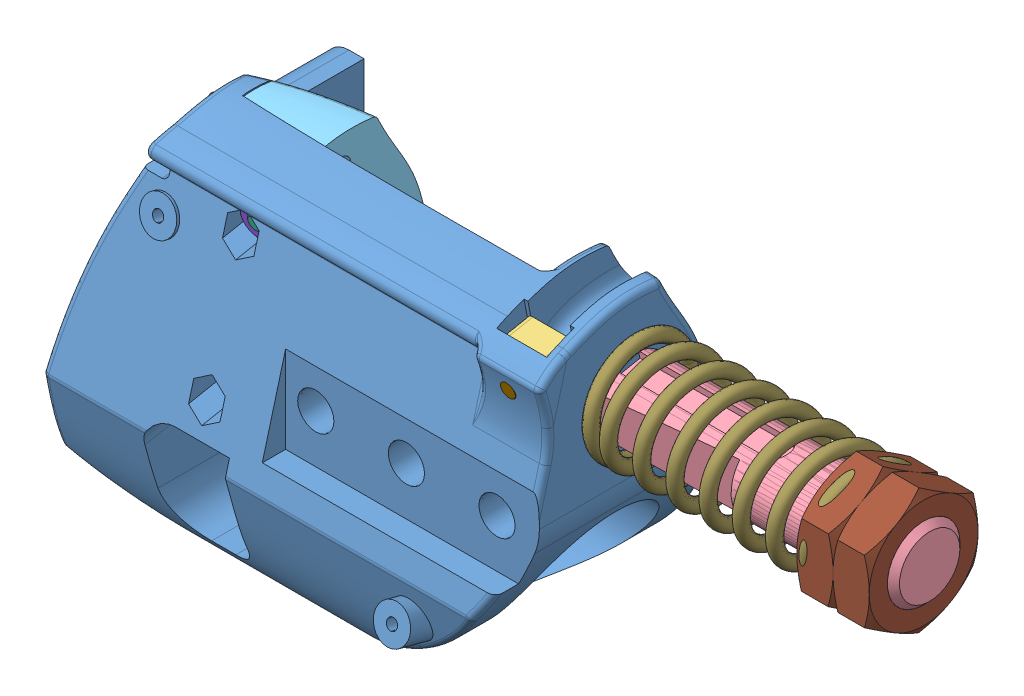
SolidWorks assembly a-motorträger-beine-rechts-v01, configuration 01. Lengths in mm.
Overall size (130.38 65.2 41.28).
22 component instances, 15 part files, 85 mates.
Components (placement in the parent):
- p-halterreferenz-rechts-v04-1: p-halterreferenz-rechts-v04 [01] at (-8 0 0) x (0 0 -1) z (1 0 0) size (41.28 65.2 84.36)
- z-jfm-0608-06-v01-1: z-jfm-0608-06-v01 [01] at (-23.3 0 0) x (-1 0 0) z (0 0 -1) size (6 12 12)
- z-induktiv-sensor-v01-1: z-induktiv-sensor-v01 [01] at (29 21.9082 7.6275) x (1 0 0) z (0 0.190809 -0.981627) size (8 16 4.7)
- z-induktiv-sensor-v01-2: z-induktiv-sensor-v01 [01] at (-25.5 8.63 4) x (0 0 -1) z (-1 0 0) size (8 16 4.7)
- p-federstössel-v01-1: p-federstössel-v01 [01] at (77.9 27.8 -1.72) x (-1 0 0) z (0 -0.190809 0.981627) size (77 12 12)
- p-halterdeckel-rechts-v02-1: p-halterdeckel-rechts-v02 [01] at (-8 0 0) x (0 0 -1) z (1 0 0) size (28.27 33.45 14.71)
- z-passschraube-misumi-4-v01-1: z-passschraube-misumi-4-v01 [01] at (-13.1 35.2829 -8.5672) x (0 -0.190809 0.981627) z (-0.839411 -0.533511 -0.103704) size (18 6.5 6.5)
- z-passschraube-misumi-4-v01-2: z-passschraube-misumi-4-v01 [01] at (-13.1 16.1412 -12.288) x (0 -0.190809 0.981627) z (-0.58333 0.797312 0.154982) size (18 6.5 6.5)
- Lock washer DIN 6799 - 7-11: Lock washer DIN 6799 - 7 [Lock washer DIN 6799 - 7] at (24 27.8 -1.72) x (0 0 1) z (-1 0 0) size (14.3 11.94 0.9)
- Hexagon Nut ISO 4032 - M2.5 - W - N-19: Hexagon Nut ISO 4032 - M2.5 - W - N [Hexagon Nut ISO 4032 - M2.5 - W - N] at (-13.1 31.8991 8.8409) x (1 0 0) z (0 -0.190809 0.981627) size (5 5.77 2)
- Hexagon Nut ISO 4032 - M2.5 - W - N-20: Hexagon Nut ISO 4032 - M2.5 - W - N [Hexagon Nut ISO 4032 - M2.5 - W - N] at (-13.1 12.7574 5.1202) x (1 0 0) z (0 -0.190809 0.981627) size (5 5.77 2)
- DIN 7991 - M3 x 8 --- 4.8C-19: DIN 7991 - M3 x 8 --- 4.8C [DIN 7991 - M3 x 8 --- 4.8C] at (-30.15 20.63 0) size (8 5.7 5.7)
- DIN 7991 - M3 x 8 --- 4.8C-20: DIN 7991 - M3 x 8 --- 4.8C [DIN 7991 - M3 x 8 --- 4.8C] at (33 34.5749 5.3527) x (0 -0.190809 0.981627) z (-0.981627 0.187303 0.036408) size (8 5.7 5.7)
- p-oese-v01-1: p-oese-v01 [01] at (-25.5 37.4 0) size (3.5 4 4)
- Hexagon Thin Nut ISO 4035 - M12 - N-19: Hexagon Thin Nut ISO 4035 - M12 - N [Hexagon Thin Nut ISO 4035 - M12 - N] at (74.9 27.8 -1.72) x (0 -0.006521 -0.999979) z (-1 0 0) size (18 20.78 6)
- Hexagon Thin Nut ISO 4035 - M12 - N-20: Hexagon Thin Nut ISO 4035 - M12 - N [Hexagon Thin Nut ISO 4035 - M12 - N] at (80.9 27.8 -1.72) x (0 0 1) z (-1 0 0) size (18 20.78 6)
- z-feder-febrotec-v01-1: z-feder-febrotec-v01 [01] at (40 28.171 -1.6479) x (1 0 0) z (0 -0.190809 0.981627) size (40.25 20.98 20.5)
- p-seil-v02-1: p-seil-v02 [01] at (-16.85 -0.1381 -7.1506) x (-1 0 0) z (0 0.190809 -0.981627) size (48.5 39 1.5)
- p-umlenkpulley-v06-1: p-umlenkpulley-v06 [01] at (-13.1 33.728 -0.5677) x (0 -0.190809 0.981627) z (-0.981627 0.187303 0.036408) size (3.6 7.15 7.15)
- p-umlenkpulley-v06-4: p-umlenkpulley-v06 [01] at (-13.1 14.5863 -4.2885) x (0 -0.190809 0.981627) z (-0.997632 0.067518 0.013124) size (3.6 7.15 7.15)
- p-umlenkpulley-v06-3: p-umlenkpulley-v06 [01] at (14.9 27.8 -1.72) x (0 -0.190809 0.981627) z (-0.981627 0.187303 0.036408) size (3.6 7.15 7.15)
- Parallel Pin ISO 2338 - 4 h6 x 10 - St-11: Parallel Pin ISO 2338 - 4 h6 x 10 - St [Parallel Pin ISO 2338 - 4 h6 x 10 - St] at (14.9 28.754 -6.6281) x (0 -0.190809 0.981627) z (-0.981627 0.187303 0.036408) size (10 4 4)
Mates (geometry in assembly coordinates):
- Deckungsgleich4: coincident anti-aligned: plane of z-jfm-0608-06-v01-1 through (-23.3 0 0) normal (0 0 -1); plane of assembly through (0 0 0) normal (0 0 1)
- Deckungsgleich22: coincident aligned: plane of p-halterreferenz-rechts-v04-1; plane of assembly through (0 0 0) normal (0 1 0)
- Deckungsgleich23: coincident anti-aligned: plane of p-halterreferenz-rechts-v04-1 through (-8 0 0) normal (0 0 -1); plane of assembly through (0 0 0) normal (0 0 1)
- Konzentrisch3: concentric aligned: cylinder of z-induktiv-sensor-v01-2 through (-30.2 20.63 0) axis (-1 0 0) radius 1.55; cylinder of p-halterreferenz-rechts-v04-1 through (38.3169 20.63 0) axis (-1 0 0) radius 1.23
- Deckungsgleich25: coincident aligned: plane of z-induktiv-sensor-v01-2; plane of p-halterreferenz-rechts-v04-1 through (-8 0 0) normal (0 0 -1)
- Deckungsgleich26: coincident anti-aligned: plane of z-induktiv-sensor-v01-2 through (-25.5 8.63 4) normal (1 0 0); plane of p-halterreferenz-rechts-v04-1 through (-25.5 0 0) normal (-1 0 0)
- Konzentrisch4: concentric aligned: cylinder of p-halterreferenz-rechts-v04-1 through (-39.3597 27.8 -1.72) axis (1 0 0) radius 6.125; cylinder of p-federstössel-v01-1 through (77.9 27.8 -1.72) axis (1 0 0) radius 6
- Parallel3: parallel anti-aligned: plane of p-halterreferenz-rechts-v04-1 through (-39.3597 22.4213 -4.6501) normal (0 0.190809 -0.981627); plane of p-federstössel-v01-1 through (65.9 20.8194 -5.1143) normal (0 -0.190809 0.981627)
- Deckungsgleich32: coincident aligned: plane of p-halterreferenz-rechts-v04-1; plane of p-halterdeckel-rechts-v02-1
- Deckungsgleich33: coincident anti-aligned: plane of p-halterdeckel-rechts-v02-1 through (-8 0 0) normal (0 0 -1); plane of assembly through (0 0 0) normal (0 0 1)
- Deckungsgleich34: coincident aligned: plane of p-halterdeckel-rechts-v02-1 through (-8 0 0) normal (1 0 0); plane of p-halterreferenz-rechts-v04-1 through (-8 0 0) normal (1 0 0)
- Konzentrisch5: concentric aligned: cylinder of p-halterdeckel-rechts-v02-1 through (-13.1 36.3949 -14.2879) axis (0 0.190809 -0.981627) radius 2.075; cylinder of z-passschraube-misumi-4-v01-1 through (-13.1 35.2829 -8.5672) axis (0 0.190809 -0.981627) radius 2
- Deckungsgleich35: coincident anti-aligned: plane of p-halterdeckel-rechts-v02-1 through (-13.1 2.3168 -11.919) normal (0 0.190809 -0.981627); plane of z-passschraube-misumi-4-v01-1 through (-14.8664 37.3885 -5.1018) normal (0 -0.190809 0.981627)
- Konzentrisch7: concentric aligned: cylinder of p-halterdeckel-rechts-v02-1 through (-13.1 17.4154 -18.843) axis (0 0.190809 -0.981627) radius 2.075; cylinder of z-passschraube-misumi-4-v01-2 through (-13.1 16.1412 -12.288) axis (0 0.190809 -0.981627) radius 2
- Deckungsgleich36: coincident anti-aligned: plane of p-halterdeckel-rechts-v02-1 through (-13.1 2.3168 -11.919) normal (0 0.190809 -0.981627); plane of z-passschraube-misumi-4-v01-2 through (-10.4602 17.4298 -8.9813) normal (0 -0.190809 0.981627)
- Konzentrisch9: concentric anti-aligned: cylinder of p-federstössel-v01-1 through (77.9 27.8 -1.72) axis (1 0 0) radius 3.5; cylinder of Lock washer DIN 6799 - 7-11 through (24.9 27.8 -1.72) axis (-1 0 0) radius 3.5
- Deckungsgleich40: coincident anti-aligned: plane of p-federstössel-v01-1 through (24.9 21.9102 -2.8649) normal (-1 0 0); plane of Lock washer DIN 6799 - 7-11 through (24.9 27.8 -1.72) normal (1 0 0)
- Konzentrisch10: concentric anti-aligned: cylinder of p-halterreferenz-rechts-v04-1 through (-13.1 27.2158 32.9346) axis (0 0.190809 -0.981627) radius 1.5; cylinder of Hexagon Nut ISO 4032 - M2.5 - W - N-19 through (-13.1 32.2808 6.8777) axis (0 -0.190809 0.981627) radius 1.025
- Parallel4: parallel anti-aligned: plane of p-halterreferenz-rechts-v04-1 through (-15.7 28.6893 33.221) normal (0.5 -0.850114 -0.165245); plane of Hexagon Nut ISO 4032 - M2.5 - W - N-19 through (-13.1 35.1145 7.4285) normal (-0.5 0.850114 0.165245)
- Deckungsgleich42: coincident anti-aligned: plane of p-halterreferenz-rechts-v04-1 through (-8 -0.1129 0.581) normal (0 -0.190809 0.981627); plane of Hexagon Nut ISO 4032 - M2.5 - W - N-19 through (-13.1 35.1145 7.4285) normal (0 0.190809 -0.981627)
- Konzentrisch11: concentric anti-aligned: cylinder of p-halterreferenz-rechts-v04-1 through (-13.1 8.0741 29.2138) axis (0 0.190809 -0.981627) radius 1.5; cylinder of Hexagon Nut ISO 4032 - M2.5 - W - N-20 through (-13.1 13.139 3.1569) axis (0 -0.190809 0.981627) radius 1.025
- Parallel5: parallel anti-aligned: plane of p-halterreferenz-rechts-v04-1 through (-15.7 9.5476 29.5002) normal (0.5 -0.850114 -0.165245); plane of Hexagon Nut ISO 4032 - M2.5 - W - N-20 through (-13.1 15.9727 3.7077) normal (-0.5 0.850114 0.165245)
- Deckungsgleich44: coincident anti-aligned: plane of p-halterreferenz-rechts-v04-1 through (-8 -0.1129 0.581) normal (0 -0.190809 0.981627); plane of Hexagon Nut ISO 4032 - M2.5 - W - N-20 through (-13.1 15.9727 3.7077) normal (0 0.190809 -0.981627)
- Konzentrisch12: concentric aligned: cylinder of z-induktiv-sensor-v01-2 through (-30.2 20.63 0) axis (-1 0 0) radius 1.55; cylinder of DIN 7991 - M3 x 8 --- 4.8C-19 through (-30.15 20.63 0) axis (-1 0 0) radius 1.5
- Deckungsgleich45: coincident aligned: cone of z-induktiv-sensor-v01-2 through (-28.5 20.63 0) axis (1 0 0); cone of DIN 7991 - M3 x 8 --- 4.8C-19 through (-29.8 20.63 0) axis (1 0 0)
- Konzentrisch14: concentric aligned: cylinder of z-induktiv-sensor-v01-1 through (33 34.5845 5.3036) axis (0 0.190809 -0.981627) radius 1.55; cylinder of DIN 7991 - M3 x 8 --- 4.8C-20 through (33 34.5749 5.3527) axis (0 0.190809 -0.981627) radius 1.5
- Deckungsgleich46: coincident aligned: cone of z-induktiv-sensor-v01-1 through (33 34.2601 6.9724) axis (0 -0.190809 0.981627); cone of DIN 7991 - M3 x 8 --- 4.8C-20 through (33 34.5082 5.6962) axis (0 -0.190809 0.981627)
- Konzentrisch16: concentric anti-aligned: cylinder of p-halterreferenz-rechts-v04-1 through (-21.3635 37.4 0) axis (1 0 0) radius 2.15; cylinder of p-oese-v01-1 through (-25.5 37.4 0) axis (-1 0 0) radius 2
- Deckungsgleich47: coincident anti-aligned: plane of p-halterreferenz-rechts-v04-1 through (-25.5 39.55 0) normal (1 0 0); plane of p-oese-v01-1 through (-25.5 39.4 0) normal (-1 0 0)
- Konzentrisch17: concentric anti-aligned: cylinder of p-federstössel-v01-1 through (77.9 27.8 -1.72) axis (1 0 0) radius 6; cylinder of Hexagon Thin Nut ISO 4035 - M12 - N-19 through (80.9 27.8 -1.72) axis (-1 0 0) radius 5.1
- Abstand16: distance = 7 mm aligned: plane of Hexagon Thin Nut ISO 4035 - M12 - N-19 through (80.9 17.4079 -1.6522) normal (1 0 0); plane of p-federstössel-v01-1 through (87.9 21.9102 -2.8649) normal (1 0 0)
- Konzentrisch19: concentric anti-aligned: cylinder of p-federstössel-v01-1 through (77.9 27.8 -1.72) axis (1 0 0) radius 6; cylinder of Hexagon Thin Nut ISO 4035 - M12 - N-20 through (86.9 27.8 -1.72) axis (-1 0 0) radius 5.1
- Deckungsgleich49: coincident anti-aligned: plane of Hexagon Thin Nut ISO 4035 - M12 - N-19 through (80.9 17.4079 -1.6522) normal (1 0 0); plane of Hexagon Thin Nut ISO 4035 - M12 - N-20 through (80.9 38.1923 -1.72) normal (-1 0 0)
- Deckungsgleich50: coincident aligned: plane of p-federstössel-v01-1 through (77.9 27.8 -1.72) normal (0 -0.190809 0.981627); plane of z-feder-febrotec-v01-1 through (40 28.171 -1.6479) normal (0 -0.190809 0.981627)
- Abstand17: distance = 3 mm aligned: plane of z-feder-febrotec-v01-1; plane of p-halterreferenz-rechts-v04-1 through (37 0 0) normal (1 0 0)
- Konzentrisch20: concentric anti-aligned: cylinder of z-passschraube-misumi-4-v01-1 through (-13.1 35.2829 -8.5672) axis (0 0.190809 -0.981627) radius 2; cylinder of p-umlenkpulley-v06-1 through (-13.1 31.4085 11.3649) axis (0 -0.190809 0.981627) radius 2.075
- Deckungsgleich52: coincident aligned: plane of p-federstössel-v01-1 through (77.9 27.8 -1.72) normal (0 -0.190809 0.981627); plane of p-umlenkpulley-v06-1
- Konzentrisch21: concentric anti-aligned: cylinder of z-passschraube-misumi-4-v01-2 through (-13.1 16.1412 -12.288) axis (0 0.190809 -0.981627) radius 2; cylinder of p-umlenkpulley-v06-4 through (-13.1 12.2668 7.6441) axis (0 -0.190809 0.981627) radius 2.075
- Deckungsgleich53: coincident aligned: plane of p-umlenkpulley-v06-1 through (-12.4179 37.5163 -1.665) normal (0 0.190809 -0.981627); plane of p-umlenkpulley-v06-4 through (-12.8541 18.4307 -5.3749) normal (0 0.190809 -0.981627)
- Konzentrisch22: concentric: cylinder of z-passschraube-misumi-4-v01-1 through (-13.1 35.2829 -8.5672) axis (0 0.190809 -0.981627) radius 2; point of p-seil-v02-1
- Konzentrisch23: concentric: cylinder of z-passschraube-misumi-4-v01-2 through (-13.1 16.1412 -12.288) axis (0 0.190809 -0.981627) radius 2; point of p-seil-v02-1
- Deckungsgleich57: coincident anti-aligned: plane of p-seil-v02-1 through (-16.85 -0.1381 -7.1506) normal (0 0.190809 -0.981627); plane of p-umlenkpulley-v06-1
- Deckungsgleich59: coincident anti-aligned: plane of p-halterreferenz-rechts-v04-1 through (-8 0 0) normal (0 0 -1); plane of assembly through (0 0 0) normal (0 0 1)
- Abstand18: distance = 8 mm aligned: plane of assembly through (0 0 0) normal (1 0 0); plane of p-halterreferenz-rechts-v04-1 through (-8 0 0) normal (1 0 0)
- Konzentrisch24: concentric aligned: cylinder of p-halterreferenz-rechts-v04-1 through (0 0 0) axis (1 0 0) radius 4.075; cylinder of z-jfm-0608-06-v01-1 through (-23.3 0 0) axis (1 0 0) radius 4
- Deckungsgleich64: coincident anti-aligned: plane of p-halterreferenz-rechts-v04-1 through (-24.3 6.25 0) normal (1 0 0); plane of z-jfm-0608-06-v01-1 through (-24.3 6 0) normal (-1 0 0)
- Parallel6: parallel aligned: plane of z-jfm-0608-06-v01-1; plane of assembly through (0 0 0) normal (0 1 0)
- Konzentrisch25: concentric aligned: cylinder of p-halterreferenz-rechts-v04-1 through (33 29.1408 33.3088) axis (0 0.190809 -0.981627) radius 1.23; cylinder of z-induktiv-sensor-v01-1 through (33 34.5845 5.3036) axis (0 0.190809 -0.981627) radius 1.55
- Deckungsgleich65: coincident anti-aligned: plane of p-halterreferenz-rechts-v04-1 through (28.85 41.4425 11.4246) normal (0 0.190809 -0.981627); plane of z-induktiv-sensor-v01-1 through (29 21.9082 7.6275) normal (0 -0.190809 0.981627)
- Parallel7: parallel anti-aligned: plane of p-halterreferenz-rechts-v04-1 through (37.15 0 0) normal (-1 0 0); plane of z-induktiv-sensor-v01-1 through (37 22.805 3.0139) normal (1 0 0)
- Konzentrisch26: concentric aligned: cylinder of p-federstössel-v01-1 through (14.9 29.1357 -8.5914) axis (0 -0.190809 0.981627) radius 2; cylinder of p-umlenkpulley-v06-3 through (14.9 25.4805 10.2126) axis (0 -0.190809 0.981627) radius 2.075
- Deckungsgleich69: coincident aligned: plane of p-federstössel-v01-1 through (77.9 27.8 -1.72) normal (0 -0.190809 0.981627); plane of p-umlenkpulley-v06-3
- Konzentrisch27: concentric anti-aligned: cylinder of p-federstössel-v01-1 through (14.9 29.1357 -8.5914) axis (0 -0.190809 0.981627) radius 2; cylinder of Parallel Pin ISO 2338 - 4 h6 x 10 - St-11 through (14.9 29.9657 -12.8615) axis (0 0.190809 -0.981627) radius 2
- Abstand19: distance = 5 mm anti-aligned: plane of p-federstössel-v01-1 through (77.9 27.8 -1.72) normal (0 -0.190809 0.981627); plane of Parallel Pin ISO 2338 - 4 h6 x 10 - St-11 through (15.2494 30.5186 -6.2851) normal (0 0.190809 -0.981627)
- Abstand20: distance = 28 mm aligned: plane of p-federstössel-v01-1; plane of p-halterreferenz-rechts-v04-1 through (-13.1 0 0) normal (-1 0 0)
- Konzentrisch190: concentric aligned: cylinder of p-halterreferenz-rechts-v04-1 through (38.3169 20.63 0) axis (-1 0 0) radius 1.23; cylinder of z-induktiv-sensor-v01-2 through (-30.2 20.63 0) axis (-1 0 0) radius 1.55
- Deckungsgleich158: coincident anti-aligned: plane of p-halterreferenz-rechts-v04-1 through (-25.5 0 0) normal (-1 0 0); plane of z-induktiv-sensor-v01-2 through (-25.5 8.63 4) normal (1 0 0)
- Konzentrisch191: concentric aligned: cylinder of p-halterreferenz-rechts-v04-1 through (-39.3597 27.8 1.72) axis (1 0 0) radius 6.05; cylinder of p-federstössel-v01-1 through (71.9 27.8 1.72) axis (1 0 0) radius 6
- Parallel16: parallel anti-aligned: plane of p-halterreferenz-rechts-v04-1; plane of p-federstössel-v01-1
- Konzentrisch192: concentric aligned: cylinder of p-halterdeckel-rechts-v02-1 through (-13.1 36.3949 14.2879) axis (0 0.190809 0.981627) radius 2; cylinder of z-passschraube-misumi-4-v01-1 through (-13.1 35.2829 8.5672) axis (0 0.190809 0.981627) radius 2
- Deckungsgleich159: coincident anti-aligned: plane of p-halterdeckel-rechts-v02-1 through (-13.1 2.3168 11.919) normal (0 0.190809 0.981627); plane of z-passschraube-misumi-4-v01-1 through (-14.8664 37.3885 5.1018) normal (0 -0.190809 -0.981627)
- Konzentrisch193: concentric aligned: cylinder of p-halterdeckel-rechts-v02-1 through (-13.1 17.4154 18.843) axis (0 0.190809 0.981627) radius 2; cylinder of z-passschraube-misumi-4-v01-2 through (-13.1 16.1412 12.288) axis (0 0.190809 0.981627) radius 2
- Deckungsgleich160: coincident anti-aligned: plane of p-halterdeckel-rechts-v02-1 through (-13.1 2.3168 11.919) normal (0 0.190809 0.981627); plane of z-passschraube-misumi-4-v01-2 through (-10.4602 17.4298 8.9813) normal (0 -0.190809 -0.981627)
- Konzentrisch194: concentric aligned: cylinder of p-federstössel-v01-1 through (71.9 27.8 1.72) axis (1 0 0) radius 3.5; cylinder of Lock washer DIN 6799 - 7-11 through (18 27.8 1.72) axis (1 0 0) radius 3.5
- Konzentrisch195: concentric anti-aligned: cylinder of p-halterreferenz-rechts-v04-1 through (-13.1 27.2158 -32.9346) axis (0 0.190809 0.981627) radius 1.5; cylinder of Hexagon Nut ISO 4032 - M2.5 - W - N-19 through (-13.1 32.2808 -6.8777) axis (0 -0.190809 -0.981627) radius 1.025
- Deckungsgleich161: coincident anti-aligned: plane of p-halterreferenz-rechts-v04-1 through (-8 -0.1129 -0.581) normal (0 -0.190809 -0.981627); plane of Hexagon Nut ISO 4032 - M2.5 - W - N-19 through (-13.1 35.1145 -7.4285) normal (0 0.190809 0.981627)
- Konzentrisch196: concentric anti-aligned: cylinder of p-halterreferenz-rechts-v04-1 through (-13.1 8.0741 -29.2138) axis (0 0.190809 0.981627) radius 1.5; cylinder of Hexagon Nut ISO 4032 - M2.5 - W - N-20 through (-13.1 13.139 -3.1569) axis (0 -0.190809 -0.981627) radius 1.025
- Deckungsgleich162: coincident anti-aligned: plane of p-halterreferenz-rechts-v04-1 through (-8 -0.1129 -0.581) normal (0 -0.190809 -0.981627); plane of Hexagon Nut ISO 4032 - M2.5 - W - N-20 through (-13.1 15.9727 -3.7077) normal (0 0.190809 0.981627)
- Konzentrisch197: concentric aligned: cylinder of z-induktiv-sensor-v01-2 through (-30.2 20.63 0) axis (-1 0 0) radius 1.55; cylinder of DIN 7991 - M3 x 8 --- 4.8C-19 through (-30.15 20.63 0) axis (-1 0 0) radius 1.5
- Deckungsgleich163: coincident aligned: cone of z-induktiv-sensor-v01-2 through (-28.5 20.63 0) axis (1 0 0); cone of DIN 7991 - M3 x 8 --- 4.8C-19 through (-29.8 20.63 0) axis (1 0 0)
- Konzentrisch198: concentric aligned: cylinder of z-induktiv-sensor-v01-1 through (33 34.5845 -5.3036) axis (0 0.190809 0.981627) radius 1.55; cylinder of DIN 7991 - M3 x 8 --- 4.8C-20 through (33 34.5749 -5.3527) axis (0 0.190809 0.981627) radius 1.5
- Deckungsgleich164: coincident aligned: cone of z-induktiv-sensor-v01-1 through (33 34.2601 -6.9724) axis (0 -0.190809 -0.981627); cone of DIN 7991 - M3 x 8 --- 4.8C-20 through (33 34.5082 -5.6962) axis (0 -0.190809 -0.981627)
- Konzentrisch199: concentric anti-aligned: cylinder of p-halterreferenz-rechts-v04-1 through (-21.3635 37.4 0) axis (1 0 0) radius 2.05; cylinder of p-oese-v01-1 through (-25.5 37.4 0) axis (-1 0 0) radius 2
- Deckungsgleich165: coincident anti-aligned: plane of p-halterreferenz-rechts-v04-1 through (-25.5 39.45 0) normal (1 0 0); plane of p-oese-v01-1 through (-25.5 39.4 0) normal (-1 0 0)
- Konzentrisch200: concentric aligned: cylinder of p-federstössel-v01-1 through (71.9 27.8 1.72) axis (1 0 0) radius 6; cylinder of Hexagon Thin Nut ISO 4035 - M12 - N-19 through (67.8963 27.8 1.72) axis (1 0 0) radius 5.1
- Konzentrisch201: concentric aligned: cylinder of p-federstössel-v01-1 through (71.9 27.8 1.72) axis (1 0 0) radius 6; cylinder of Hexagon Thin Nut ISO 4035 - M12 - N-20 through (73.8963 27.8 1.72) axis (1 0 0) radius 5.1
- Konzentrisch202: concentric anti-aligned: cylinder of z-passschraube-misumi-4-v01-1 through (-13.1 35.2829 8.5672) axis (0 0.190809 0.981627) radius 2; cylinder of p-umlenkpulley-v06-1 through (-13.1 31.4085 -11.3649) axis (0 -0.190809 -0.981627) radius 2
- Konzentrisch203: concentric anti-aligned: cylinder of z-passschraube-misumi-4-v01-2 through (-13.1 16.1412 12.288) axis (0 0.190809 0.981627) radius 2; cylinder of p-umlenkpulley-v06-4 through (-13.1 12.2668 -7.6441) axis (0 -0.190809 -0.981627) radius 2
- Deckungsgleich166: coincident aligned: plane of p-umlenkpulley-v06-1 through (-12.4322 37.444 1.6791) normal (0 0.190809 0.981627); plane of p-umlenkpulley-v06-4 through (-12.8593 18.3573 5.3892) normal (0 0.190809 0.981627)
- Konzentrisch204: concentric aligned: cylinder of p-halterreferenz-rechts-v04-1 through (0 0 0) axis (1 0 0) radius 4; cylinder of z-jfm-0608-06-v01-1 through (-23.1 0 0) axis (1 0 0) radius 4
- Deckungsgleich167: coincident anti-aligned: plane of p-halterreferenz-rechts-v04-1 through (-24.1 6.25 0) normal (1 0 0); plane of z-jfm-0608-06-v01-1 through (-24.1 6 0) normal (-1 0 0)
- Konzentrisch205: concentric aligned: cylinder of p-halterreferenz-rechts-v04-1 through (33 29.1408 -33.3088) axis (0 0.190809 0.981627) radius 1.23; cylinder of z-induktiv-sensor-v01-1 through (33 34.5845 -5.3036) axis (0 0.190809 0.981627) radius 1.55
- Deckungsgleich168: coincident anti-aligned: plane of p-halterreferenz-rechts-v04-1 through (28.85 41.4425 -11.4246) normal (0 0.190809 0.981627); plane of z-induktiv-sensor-v01-1 through (37 21.9082 -7.6275) normal (0 -0.190809 -0.981627)
- Konzentrisch206: concentric aligned: cylinder of p-federstössel-v01-1 through (8.9 29.1357 8.5914) axis (0 -0.190809 -0.981627) radius 2; cylinder of p-umlenkpulley-v06-3 through (8.9 25.4805 -10.2126) axis (0 -0.190809 -0.981627) radius 2
- Konzentrisch207: concentric anti-aligned: cylinder of p-federstössel-v01-1 through (8.9 29.1357 8.5914) axis (0 -0.190809 -0.981627) radius 2; cylinder of Parallel Pin ISO 2338 - 4 h6 x 10 - St-11 through (8.9 29.9657 12.8615) axis (0 0.190809 0.981627) radius 2
